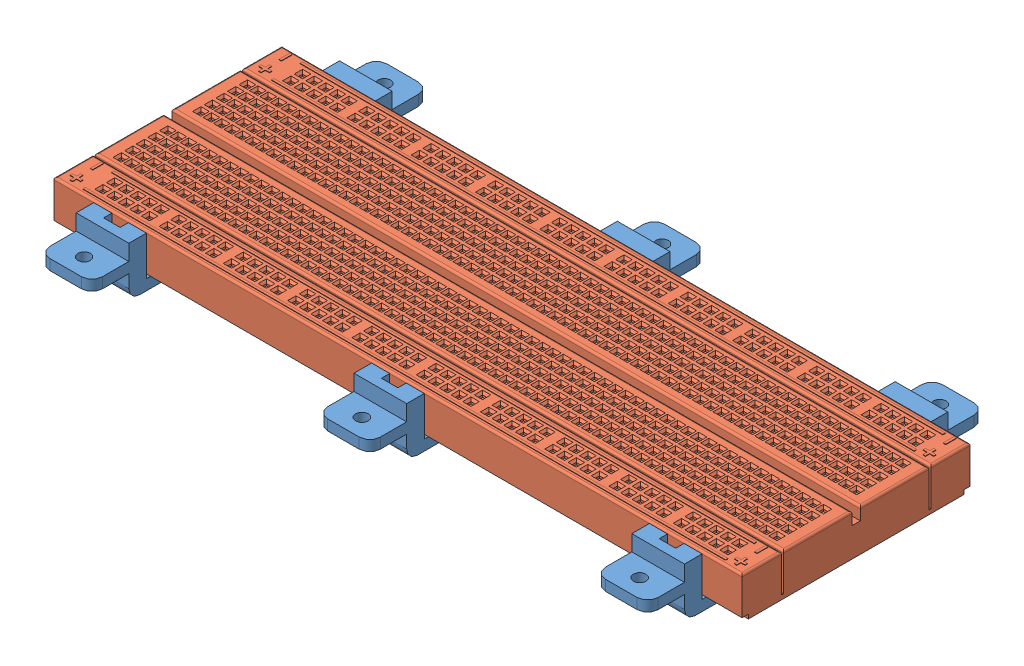
SolidWorks assembly Breadboard Assembly, configuration Default. Lengths in mm.
Overall size (166 12.64 81.28).
4 component instances, 2 part files, 12 mates.
Components (placement in the parent):
- Breadboard Mount-1: Breadboard Mount [Default] at origin size (12.7 12.06 81.28)
- Breadboard-1: Breadboard [Default] at (-16.0061 3.54 -27.4979) x (0 0 1) z (-1 0 0) size (57 10.1 166)
- Breadboard Mount-3: Breadboard Mount [Default] at (66.9878 0 0) size (12.7 12.06 81.28)
- Breadboard Mount-4: Breadboard Mount [Default] at (133.9878 0 0) size (12.7 12.06 81.28)
Mates (geometry in assembly coordinates):
- Coincident1: coincident: plane of Breadboard Mount-1 through (0 0 0) normal (0 1 0); plane of assembly through (0 0 0) normal (0 1 0)
- Coincident2: coincident: plane of Breadboard Mount-1 through (0 0 0) normal (1 0 0); plane of assembly through (0 0 0) normal (1 0 0)
- Coincident3: coincident: plane of Breadboard Mount-1 through (0 0 0) normal (0 0 1); plane of assembly through (0 0 0) normal (0 0 1)
- Coincident4: coincident: plane of Breadboard Mount-1 through (0 2.54 0) normal (0 1 0); plane of Breadboard-1 through (66.9939 2.54 0.0021) normal (0 -1 0)
- Coincident5: coincident: plane of Breadboard Mount-1 through (1.9939 12.065 27.4955) normal (-1 0 0); plane of Breadboard-1 through (1.9939 3.54 27.5021) normal (1 0 0)
- Coincident6: coincident: plane of Breadboard Mount-1 through (1.9939 12.065 29.5021) normal (0 0 -1); plane of Breadboard-1 through (-0.0061 6.04 29.5021) normal (0 0 1)
- Coincident7: coincident: plane of Breadboard-1 through (66.9939 2.54 0.0021) normal (0 -1 0); plane of Breadboard Mount-3 through (66.9878 2.54 0) normal (0 1 0)
- Coincident8: coincident: plane of Breadboard-1 through (66.9939 6.04 29.5021) normal (0 0 1); plane of Breadboard Mount-3 through (68.9817 12.065 29.5021) normal (0 0 -1)
- Coincident9: coincident: plane of Breadboard-1 through (64.9939 8.54 27.5021) normal (-1 0 0); plane of Breadboard Mount-3 through (64.9939 12.065 29.5021) normal (1 0 0)
- Coincident10: coincident: plane of Breadboard-1 through (66.9939 2.54 0.0021) normal (0 -1 0); plane of Breadboard Mount-4 through (133.9878 2.54 0) normal (0 1 0)
- Coincident11: coincident: plane of Breadboard-1 through (131.9939 8.54 27.5021) normal (-1 0 0); plane of Breadboard Mount-4 through (131.9939 12.065 29.5021) normal (1 0 0)
- Coincident12: coincident: plane of Breadboard-1 through (133.9939 6.04 29.5021) normal (0 0 1); plane of Breadboard Mount-4 through (135.9817 12.065 29.5021) normal (0 0 -1)
